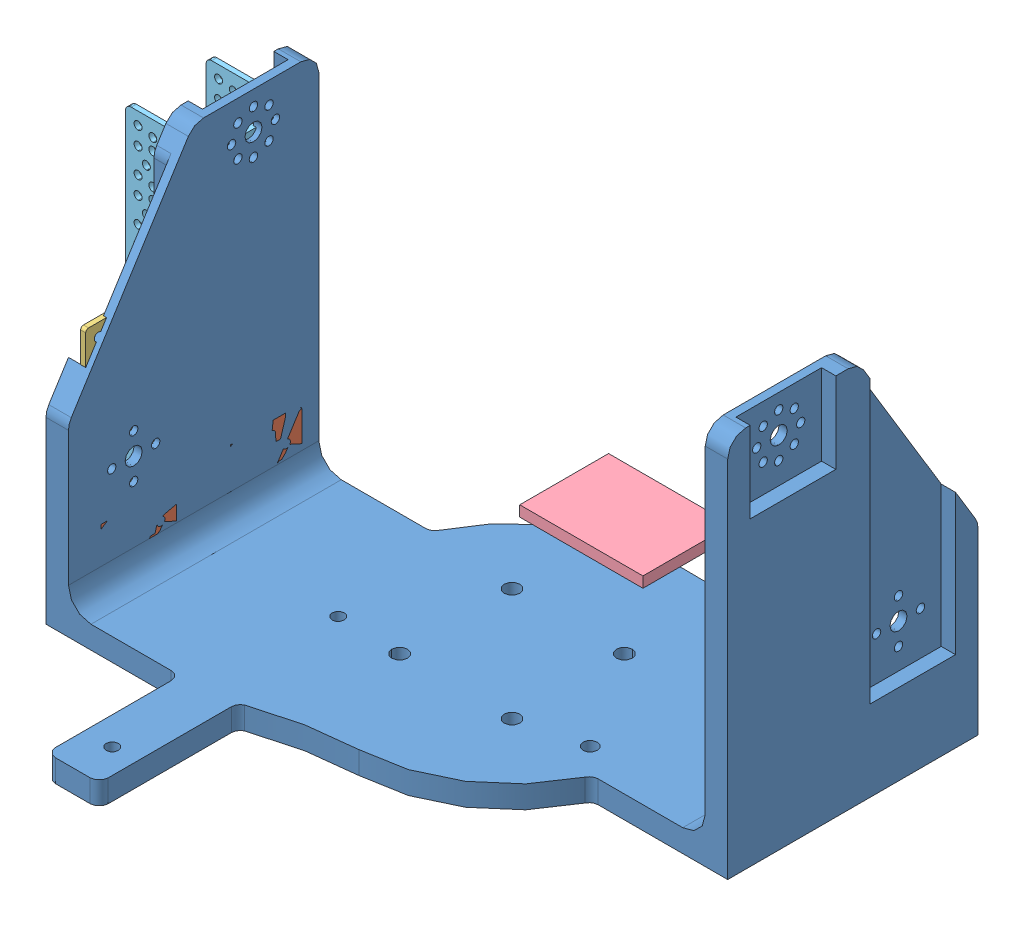
SolidWorks assembly Assem2, configuration Défaut. Lengths in mm.
Overall size (280.39 171.9 233.74).
6 component instances, 5 part files, 12 mates.
Components (placement in the parent):
- ARMUS-REV2-001-1: ARMUS-REV2-001 [Default] at origin size (250 170 233.74)
- ARMUS-REV2-010-1: ARMUS-REV2-010 [Default] at (-98.236 -1.9 53.2841) x (0 0 1) z (-1 0 0) size (38.1 38.1 38.1)
- ARMUS-REV2-011-1: ARMUS-REV2-011 [Default] at (-117.286 36.2 53.2841) x (0 -1 0) z (0 0 -1) size (114.3 2.29 38.1)
- ARMUS-REV2-013-1: ARMUS-REV2-013 [Default] at (-48.7811 12.098 -52.2254) size (54.8 4.76 39.51)
- ARMUS-REV2-010-2: ARMUS-REV2-010 [Default] at (-98.236 0 -2.5098) x (0 0 1) z (-1 0 0) size (38.1 38.1 38.1)
- ARMUS-REV2-012-1: ARMUS-REV2-012 [Default] at (-117.286 152.4 -21.5598) x (0 0 1) z (0 -1 0) size (38.1 38.1 152.4)
Mates (geometry in assembly coordinates):
- Coincident1: coordinate: point of ARMUS-REV2-001-1
- Parallel1: parallel aligned: plane of ARMUS-REV2-001-1 through (-66.175 0 82.2941) normal (0 0 1); plane of ARMUS-REV2-011-1 through (-119.572 74.3 72.3341) normal (0 0 1)
- Concentric2: concentric aligned: cylinder of ARMUS-REV2-001-1 through (125.001 55.25 53.2841) axis (-1 0 0) radius 3.81; cylinder of ARMUS-REV2-011-1 through (-119.572 55.25 53.2841) axis (-1 0 0) radius 6.3627
- Concentric3: concentric aligned: cylinder of ARMUS-REV2-010-1 through (-117.286 17.15 53.2841) axis (-1 0 0) radius 6.3627; cylinder of ARMUS-REV2-011-1 through (-119.572 17.15 53.2841) axis (-1 0 0) radius 6.3627
- Concentric5: concentric aligned: cylinder of ARMUS-REV2-010-1 through (-117.286 30.6204 66.7545) axis (-1 0 0) radius 1.778; cylinder of ARMUS-REV2-011-1 through (-119.572 30.6204 66.7545) axis (-1 0 0) radius 1.778
- Coincident4: coincident anti-aligned: plane of ARMUS-REV2-010-1 through (-117.286 0.386 34.2341) normal (-1 0 0); plane of ARMUS-REV2-011-1 through (-117.286 36.2 53.2841) normal (1 0 0)
- Coincident5: coincident aligned: plane of ARMUS-REV2-001-1 through (-115 170 -141.6255) normal (1 0 0); plane of ARMUS-REV2-010-1 through (-115 -1.9 53.2841) normal (1 0 0)
- Coincident6: coincident aligned: plane of ARMUS-REV2-010-1 through (-115 -1.9 53.2841) normal (1 0 0); plane of ARMUS-REV2-010-2 through (-115 0 -2.5098) normal (1 0 0)
- Concentric6: concentric anti-aligned: cylinder of ARMUS-REV2-010-2 through (-117.286 19.05 -2.5098) axis (-1 0 0) radius 6.3627; cylinder of ARMUS-REV2-012-1 through (-117.286 19.05 -2.5098) axis (1 0 0) radius 6.3627
- Coincident7: coincident anti-aligned: plane of ARMUS-REV2-010-2 through (-117.286 2.286 -21.5598) normal (-1 0 0); plane of ARMUS-REV2-012-1 through (-117.286 0 16.5402) normal (1 0 0)
- Concentric7: concentric anti-aligned: cylinder of ARMUS-REV2-010-2 through (-117.286 5.5796 -15.9802) axis (-1 0 0) radius 1.778; cylinder of ARMUS-REV2-012-1 through (-117.286 5.5796 -15.9802) axis (1 0 0) radius 1.778
- Coincident9: coincident aligned: plane of ARMUS-REV2-001-1 through (0 0 0) normal (0 -1 0); plane of ARMUS-REV2-010-2 through (-98.236 0 -2.5098) normal (0 -1 0)
